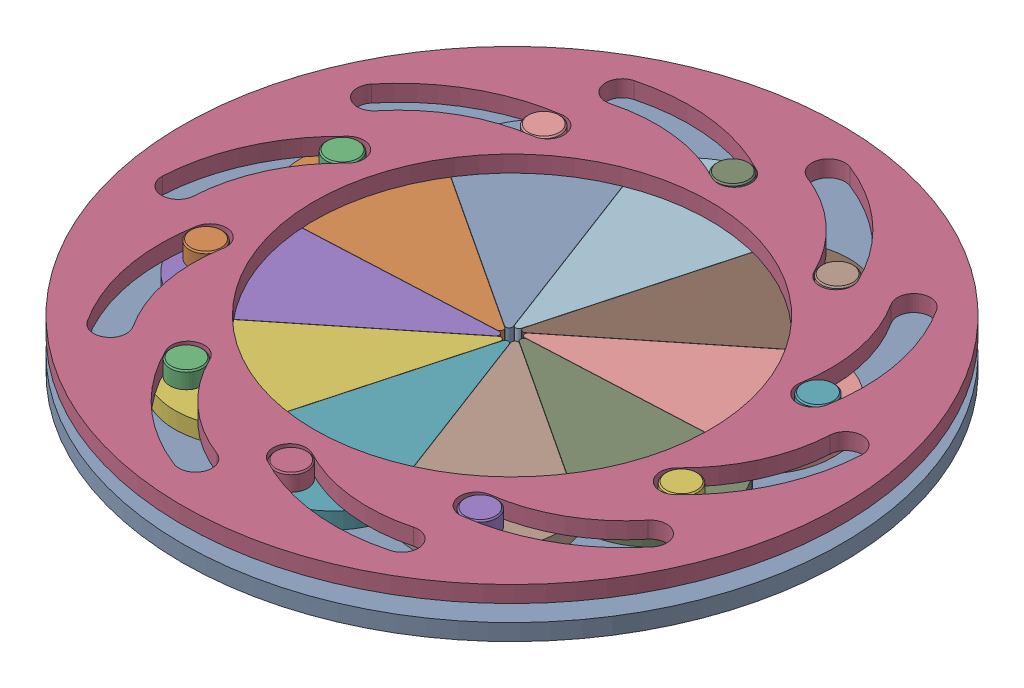
SolidWorks assembly Assembly, configuration Default. Lengths in mm.
Overall size (255.95 20 255.95).
22 component instances, 4 part files, 8 mates.
Components (placement in the parent):
- Base-1: Base [Default] at (24.342 47.5413 107.6248) size (200 5 200)
- Shutter-1: Shutter [Default] at (23.9625 57.5413 108.5563) x (-0.263161 0 0.964752) z (0.964752 0 0.263161) size (41.26 15 77.76)
- Rod-1: Rod [Default] at (-44.9584 52.5413 89.7563) x (0.743811 0 0.66839) z (-0.66839 0 0.743811) size (10 10 10)
- Spinner-4: Spinner [Default] at (24.342 62.5413 107.6248) x (-0.940811 0 -0.338931) z (-0.338931 0 0.940811) size (200 5 200)
- Shutter-2: Shutter [Default] at (24.5825 57.5413 108.6015) x (0.354165 0 0.935183) z (0.935183 0 -0.354165) size (41.26 15 77.76)
- Shutter-3: Shutter [Default] at (25.1107 57.5413 108.2737) x (0.836212 0 0.548406) z (0.548406 0 -0.836212) size (41.26 15 77.76)
- Shutter-4: Shutter [Default] at (25.3453 57.5413 107.698) x (0.998855 0 -0.047843) z (-0.047843 0 -0.998855) size (41.26 15 77.76)
- Shutter-5: Shutter [Default] at (25.1967 57.5413 107.0943) x (0.779969 0 -0.625818) z (-0.625818 0 -0.779969) size (41.26 15 77.76)
- Shutter-6: Shutter [Default] at (24.7216 57.5413 106.6933) x (0.263161 0 -0.964752) z (-0.964752 0 -0.263161) size (41.26 15 77.76)
- Shutter-7: Shutter [Default] at (24.1016 57.5413 106.6481) x (-0.354165 0 -0.935183) z (-0.935183 0 0.354165) size (41.26 15 77.76)
- Shutter-8: Shutter [Default] at (23.5734 57.5413 106.976) x (-0.836212 0 -0.548406) z (-0.548406 0 0.836212) size (41.26 15 77.76)
- Shutter-9: Shutter [Default] at (23.3388 57.5413 107.5517) x (-0.998855 0 0.047843) z (0.047843 0 0.998855) size (41.26 15 77.76)
- Shutter-10: Shutter [Default] at (23.4874 57.5413 108.1553) x (-0.779969 0 0.625818) z (0.625818 0 0.779969) size (41.26 15 77.76)
- Rod-2: Rod [Default] at (-42.226 52.5413 133.9027) x (0.994626 0 0.103538) z (-0.103538 0 0.994626) size (10 10 10)
- Rod-3: Rod [Default] at (-14.0669 52.5413 168.0118) x (0.865527 0 -0.500863) z (0.500863 0 0.865527) size (10 10 10)
- Rod-4: Rod [Default] at (28.7631 52.5413 179.0552) x (0.405826 0 -0.91395) z (0.91395 0 0.405826) size (10 10 10)
- Rod-5: Rod [Default] at (69.9045 52.5413 162.8145) x (-0.208886 0 -0.97794) z (0.97794 0 -0.208886) size (10 10 10)
- Rod-6: Rod [Default] at (93.6425 52.5413 125.4933) x (-0.743811 0 -0.66839) z (0.66839 0 -0.743811) size (10 10 10)
- Rod-7: Rod [Default] at (90.9101 52.5413 81.3469) x (-0.994626 0 -0.103538) z (0.103538 0 -0.994626) size (10 10 10)
- Rod-8: Rod [Default] at (62.751 52.5413 47.2378) x (-0.865527 0 0.500863) z (-0.500863 0 -0.865527) size (10 10 10)
- Rod-9: Rod [Default] at (19.921 52.5413 36.1945) x (-0.405826 0 0.91395) z (-0.91395 0 -0.405826) size (10 10 10)
- Rod-10: Rod [Default] at (-21.2204 52.5413 52.4351) x (0.208886 0 0.97794) z (-0.97794 0 0.208886) size (10 10 10)
Mates (geometry in assembly coordinates):
- Coincident2: coincident anti-aligned: plane of Base-1 through (24.342 52.5413 107.6248) normal (0 1 0); plane of Shutter-1 through (20.8405 52.5413 107.7047) normal (0 -1 0)
- Slot1: slot anti-aligned: cylinder of Base-1; cylinder of Shutter-1 through (-36.8159 42.5413 91.9774) axis (0 1 0) radius 1.5; cylinder of Base-1 through (-35.5745 52.5413 88.1568) axis (0 -1 0) radius 1.5
- Concentric3: concentric anti-aligned: cylinder of Shutter-1 through (-44.9584 52.5413 89.7563) axis (0 1 0) radius 5; cylinder of Rod-1 through (-44.9584 62.5413 89.7563) axis (0 -1 0) radius 5
- Coincident3: coincident aligned: plane of Shutter-1 through (20.8405 52.5413 107.7047) normal (0 -1 0); circle of Rod-1
- Parallel4: parallel anti-aligned: plane of Shutter-1 through (20.8405 57.5413 107.7047) normal (0 1 0); plane of Spinner-4 through (24.342 57.5413 107.6248) normal (0 -1 0)
- Coincident9: coincident anti-aligned: plane of Shutter-1 through (20.8405 57.5413 107.7047) normal (0 1 0); plane of Spinner-4 through (24.342 57.5413 107.6248) normal (0 -1 0)
- Concentric5: concentric anti-aligned: cylinder of Base-1 through (24.342 52.5413 107.6248) axis (0 -1 0) radius 100; cylinder of Spinner-4 through (24.342 57.5413 107.6248) axis (0 1 0) radius 100
- Slot3: slot anti-aligned: cylinder of Spinner-4 through (-7.6311 57.5413 127.0692) axis (0 1 0) radius 57.7786; cylinder of Rod-1 through (-44.9584 62.5413 89.7563) axis (0 -1 0) radius 5; cylinder of Spinner-4 through (-44.2122 57.5413 89.0244) axis (0 1 0) radius 5
